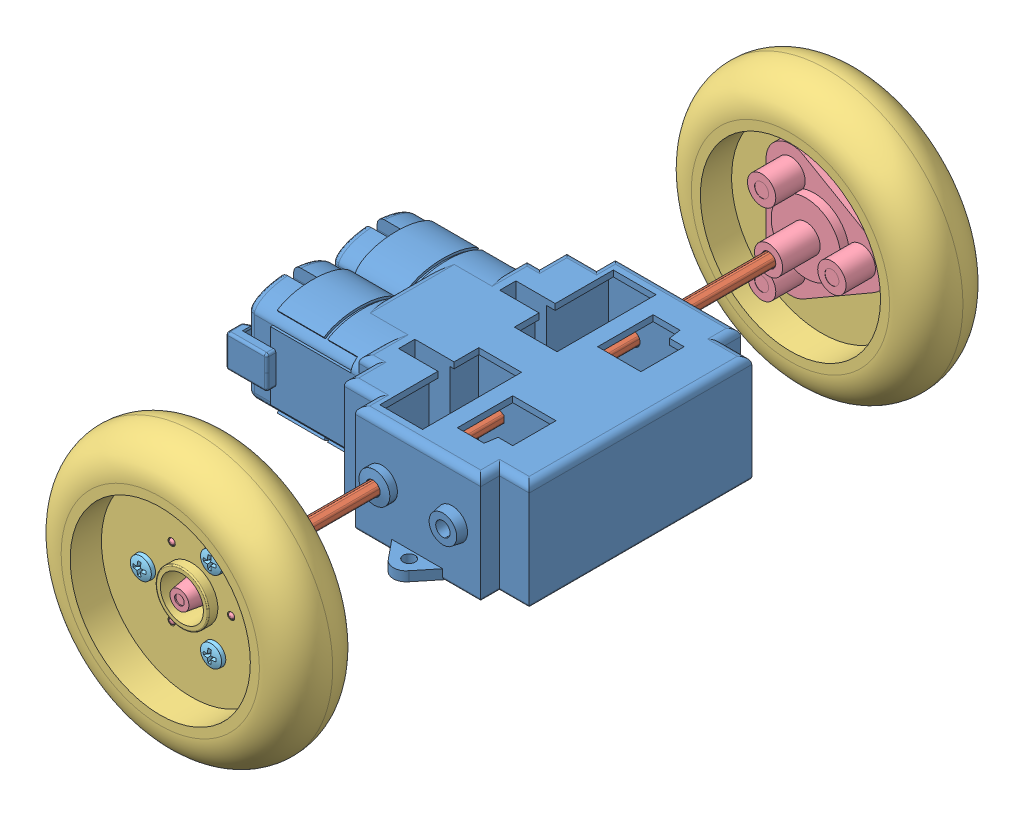
SolidWorks assembly Base_Motor_Assembly, configuration Default. Lengths in mm.
Overall size (81.13 78.43 148.79).
13 component instances, 5 part files, 31 mates.
Components (placement in the parent):
- Base _Motor-1: Base _Motor [Default] at (-3.0912 -7.3575 6.6298) size (69.09 23.66 65.09)
- Base_Motor_Axle-1: Base_Motor_Axle [Default] at (3.7736 3.9455 8.3157) x (0.888291 0.459281 0) z (0 0 1) size (2.77 2.58 60.96)
- Base_Motor_Axle-4: Base_Motor_Axle [Default] at (3.7736 3.9455 4.9439) x (-0.841894 -0.539643 0) z (0 0 -1) size (2.77 2.58 60.96)
- Base_Wheel-1: Base_Wheel [Default] at (3.7736 3.9455 65.5165) x (0.866025 -0.5 0) z (0 0 1) size (57.42 57.42 15.51)
- Base_Wheel_AxleInsert-1: Base_Wheel_AxleInsert [Default] at (3.7736 3.9455 70.5965) x (0.866025 -0.5 0) z (0 0 1) size (27.72 25.44 16.08)
- Base_Wheel-2: Base_Wheel [Default] at (3.7736 3.9455 -67.7661) x (0.866025 0.5 0) z (0 0 1) size (57.42 57.42 15.51)
- Base_Wheel_AxleInsert-2: Base_Wheel_AxleInsert [Default] at (3.7736 3.9455 -57.3369) x (0.866025 -0.5 0) z (0 0 -1) size (27.72 25.44 16.08)
- binding head screw_ai-3: binding head screw_ai [CR-BHMS 0.086-64x0.25x0.25-S] at (-6.1324 3.9455 75.6917) x (0 0 -1) z (1 0 0) size (7.6 4.6 4.6)
- binding head screw_ai-4: binding head screw_ai [CR-BHMS 0.086-64x0.25x0.25-S] at (8.7266 -4.6334 75.6917) x (0 0 -1) z (1 0 0) size (7.6 4.6 4.6)
- binding head screw_ai-5: binding head screw_ai [CR-BHMS 0.086-64x0.25x0.25-S] at (8.7266 12.5243 75.6917) x (0 0 -1) z (1 0 0) size (7.6 4.6 4.6)
- binding head screw_ai-6: binding head screw_ai [CR-BHMS 0.086-64x0.25x0.25-S] at (-1.1794 12.5243 -62.4321) x (0 0 1) z (-1 0 0) size (7.6 4.6 4.6)
- binding head screw_ai-7: binding head screw_ai [CR-BHMS 0.086-64x0.25x0.25-S] at (-1.1794 -4.6334 -62.4321) x (0 0 1) z (-1 0 0) size (7.6 4.6 4.6)
- binding head screw_ai-8: binding head screw_ai [CR-BHMS 0.086-64x0.25x0.25-S] at (13.6796 3.9455 -62.4321) x (0 0 1) z (-1 0 0) size (7.6 4.6 4.6)
Mates (geometry in assembly coordinates):
- Concentric2: concentric: cylinder of Base_Wheel-1 through (-0.4174 11.2045 60.4517) axis (0 0 1) radius 0.762; cylinder of Base_Wheel_AxleInsert-1 through (-0.4174 11.2045 72.1205) axis (0 0 -1) radius 0.635
- Concentric3: concentric: cylinder of Base_Wheel-1 through (12.1556 3.9455 60.4517) axis (0 0 1) radius 0.762; cylinder of Base_Wheel_AxleInsert-1 through (12.1556 3.9455 72.1205) axis (0 0 -1) radius 0.635
- Concentric4: concentric: cylinder of Base_Wheel-1 through (-0.4174 -3.3135 60.4517) axis (0 0 1) radius 0.762; cylinder of Base_Wheel_AxleInsert-1 through (-0.4174 -3.3135 72.1205) axis (0 0 -1) radius 0.635
- Coincident13: coincident: plane of Base_Wheel-1 through (3.7736 3.9455 69.5805) normal (0 0 -1); plane of Base_Wheel_AxleInsert-1 through (8.7266 12.5243 69.5805) normal (0 0 1)
- Coincident14: coincident: plane of Base_Motor_Axle-1 through (2.5036 3.2123 69.2757) normal (-0.5 -0.866025 0); plane of Base_Wheel_AxleInsert-1 through (3.7736 2.479 73.0857) normal (0.5 0.866025 0)
- Coincident16: coincident: plane of Base_Motor_Axle-1 through (3.7736 2.479 69.2757) normal (0.5 -0.866025 0); plane of Base_Wheel_AxleInsert-1 through (5.0436 3.2123 73.0857) normal (-0.5 0.866025 0)
- Distance3: distance = 6.35 mm: plane of Base_Motor_Axle-1 through (3.7736 3.9455 69.2757) normal (0 0 1); plane of Base_Wheel_AxleInsert-1 through (3.7736 3.9455 75.6257) normal (0 0 -1)
- Concentric5: concentric: cylinder of Base_Wheel-2 through (-4.6084 3.9455 -67.7509) axis (0 0 1) radius 0.762; cylinder of Base_Wheel_AxleInsert-2 through (-4.6084 3.9455 -58.8609) axis (0 0 1) radius 0.635
- Concentric6: concentric: cylinder of Base_Wheel-2 through (7.9646 -3.3135 -67.7509) axis (0 0 1) radius 0.762; cylinder of Base_Wheel_AxleInsert-2 through (7.9646 -3.3135 -58.8609) axis (0 0 1) radius 0.635
- Coincident18: coincident: plane of Base_Wheel-2 through (3.7736 3.9455 -56.3209) normal (0 0 1); plane of Base_Wheel_AxleInsert-2 through (-1.1794 -4.6334 -56.3209) normal (0 0 -1)
- Coincident19: coincident: plane of Base_Motor_Axle-4 through (3.7736 5.412 -56.0161) normal (0.5 0.866025 0); plane of Base_Wheel_AxleInsert-2 through (5.0436 4.6787 -59.8261) normal (-0.5 -0.866025 0)
- Coincident20: coincident: plane of Base_Motor_Axle-4 through (2.5036 4.6787 -56.0161) normal (-0.5 0.866025 0); plane of Base_Wheel_AxleInsert-2 through (3.7736 5.412 -59.8261) normal (0.5 -0.866025 0)
- Distance4: distance = 6.35 mm: plane of Base_Motor_Axle-4 through (3.7736 3.9455 -56.0161) normal (0 0 -1); plane of Base_Wheel_AxleInsert-2 through (3.7736 3.9455 -62.3661) normal (0 0 1)
- Concentric8: concentric: cylinder of Base_Wheel-1 through (-6.1324 3.9455 60.4517) axis (0 0 1) radius 1.524; cylinder of binding head screw_ai-3 through (-6.1324 3.9455 98.5517) axis (0 0 1) radius 1.0922
- Coincident23: coincident: plane of Base_Wheel-1 through (3.7736 3.9455 71.8817) normal (0 0 1); plane of binding head screw_ai-3 through (-6.1324 5.0377 71.8817) normal (0 0 -1)
- Concentric9: concentric: cylinder of Base_Wheel-1 through (8.7266 -4.6334 60.4517) axis (0 0 1) radius 1.524; cylinder of binding head screw_ai-4 through (8.7266 -4.6334 98.5517) axis (0 0 1) radius 1.0922
- Coincident24: coincident: plane of Base_Wheel-1 through (3.7736 3.9455 71.8817) normal (0 0 1); plane of binding head screw_ai-4 through (8.7266 -3.5412 71.8817) normal (0 0 -1)
- Concentric10: concentric: cylinder of Base_Wheel-1 through (8.7266 12.5243 60.4517) axis (0 0 1) radius 1.524; cylinder of binding head screw_ai-5 through (8.7266 12.5243 98.5517) axis (0 0 1) radius 1.0922
- Coincident25: coincident: plane of Base_Wheel-1 through (3.7736 3.9455 71.8817) normal (0 0 1); plane of binding head screw_ai-5 through (8.7266 13.6165 71.8817) normal (0 0 -1)
- Concentric11: concentric: cylinder of Base_Wheel-2 through (-1.1794 12.5243 -67.7509) axis (0 0 1) radius 1.524; cylinder of binding head screw_ai-6 through (-1.1794 12.5243 -85.2921) axis (0 0 -1) radius 1.0922
- Coincident26: coincident: plane of Base_Wheel-2 through (3.7736 3.9455 -58.6221) normal (0 0 -1); plane of binding head screw_ai-6 through (-1.1794 13.6165 -58.6221) normal (0 0 1)
- Concentric12: concentric: cylinder of Base_Wheel-2 through (-1.1794 -4.6334 -67.7509) axis (0 0 1) radius 1.524; cylinder of binding head screw_ai-7 through (-1.1794 -4.6334 -85.2921) axis (0 0 -1) radius 1.0922
- Coincident27: coincident: plane of Base_Wheel-2 through (3.7736 3.9455 -58.6221) normal (0 0 -1); plane of binding head screw_ai-7 through (-1.1794 -3.5412 -58.6221) normal (0 0 1)
- Concentric13: concentric: cylinder of Base_Wheel-2 through (13.6796 3.9455 -67.7509) axis (0 0 1) radius 1.524; cylinder of binding head screw_ai-8 through (13.6796 3.9455 -85.2921) axis (0 0 -1) radius 1.0922
- Coincident28: coincident: plane of Base_Wheel-2 through (3.7736 3.9455 -58.6221) normal (0 0 -1); plane of binding head screw_ai-8 through (13.6796 5.0377 -58.6221) normal (0 0 1)
- Wspólnie9: coincident: plane of Base _Motor-1 through (5.0436 4.6787 -1.2601) normal (-1 0 0); plane of Base_Motor_Axle-4 through (5.0436 4.6787 -56.0161) normal (1 0 0)
- Wspólnie10: coincident: plane of Base _Motor-1 through (3.7736 5.412 -1.2601) normal (-0.5 -0.866025 0); plane of Base_Motor_Axle-4 through (3.7736 5.412 -56.0161) normal (0.5 0.866025 0)
- Wspólnie11: coincident: plane of Base _Motor-1 through (3.7736 5.412 -1.2601) normal (-0.5 -0.866025 0); plane of Base_Motor_Axle-1 through (5.0436 4.6787 69.2757) normal (0.5 0.866025 0)
- Wspólnie12: coincident: plane of Base _Motor-1 through (5.0436 4.6787 -1.2601) normal (-1 0 0); plane of Base_Motor_Axle-1 through (5.0436 3.2123 69.2757) normal (1 0 0)
- Odległość1: distance = 1.27 mm: plane of Base_Motor_Axle-1 through (3.7736 3.9455 8.3157) normal (0 0 -1); plane of Base _Motor-1 through (-0.348 13.9785 9.5857) normal (0 0 1)
- Odległość2: distance = 1.27 mm: plane of Base _Motor-1 through (-0.348 13.9785 3.6739) normal (0 0 -1); plane of Base_Motor_Axle-4 through (3.7736 3.9455 4.9439) normal (0 0 1)
